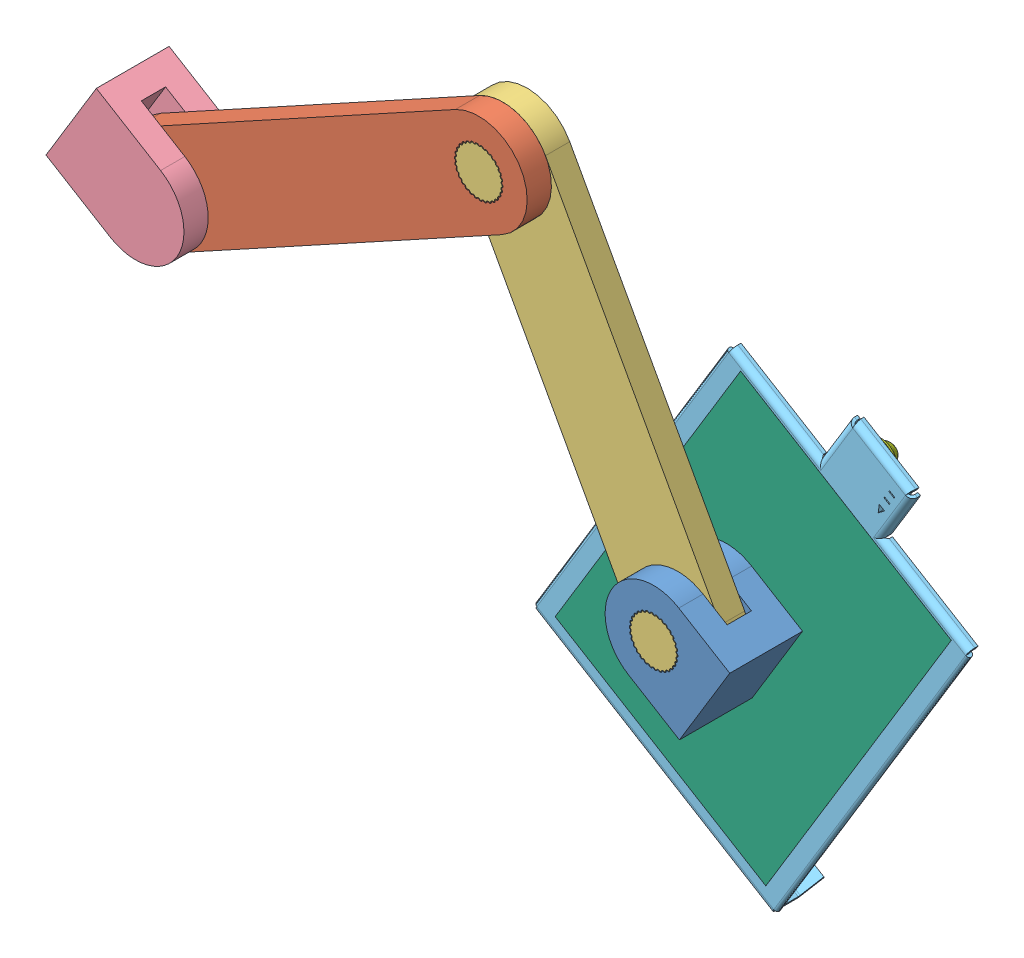
SolidWorks assembly movies, configuration Default. Lengths in mm.
Overall size (844.27 585.2 400.69).
9 component instances, 7 part files, 4 mates.
Components (placement in the parent):
- movie screen arm-1: movie screen arm [Default] at (19.653 64.9942 60.0694) size (271.91 188.53 40) (flexible)
  - Screen Arm Mount-1: Screen Arm Mount [Default] at (460.6698 -286.8749 -10.3389) x (-0.518973 -0.85479 0) z (0 0 1) size (40 44.59 30)
  - Arm 1-1: Arm 1 [Default] at (319.3618 -78.7079 -0.3389) x (0.480784 -0.876839 0) z (0.876839 0.480784 0) size (40 10 190)
  - Arm 2-1: Arm 2 [Default] at (269.2199 -30.9413 -20.3389) x (-0.876839 -0.480784 0) z (0 0 1) size (40 190 20)
  - mount thing do wak-1: mount thing do wak [Default] at (185.9995 -147.4762 -10.3389) x (-0.518973 -0.85479 0) z (0 0 1) size (40 50.99 30)
- sweet screen-1: sweet screen [Default] at (440.6658 467.0414 657.6815) x (0.167909 -0.686882 0.707107) z (0.167909 -0.686882 -0.707107) size (283.33 771.18 283.33)
  - Frame-1: Frame [Default] at (20.3068 185.0949 880.7989) size (283.33 771.18 283.33)
  - glass panel for god screen-1: glass panel for god screen [Default] at (-40.715 166.9153 847.3418) x (0.5 0.707107 0.5) z (-0.707107 0 0.707107) size (147.32 101.6 2.54)
  - Button Dial-1: Button Dial [Default] at (-81.6373 96.2697 838.5954) x (0.5 -0.707107 0.5) z (0.5 0.707107 0.5) size (15.23 13.25 15.23)
Mates (geometry in assembly coordinates):
- Coincident1: coincident anti-aligned: plane of movie screen arm-1/Screen Arm Mount-1 through (409.296 -141.8903 29.7305) normal (0 0 -1); plane of sweet screen-1/glass panel for god screen-1 through (413.9643 -126.6514 29.7305) normal (0 0 1)
- Width1: width aligned: plane of sweet screen-1/Frame-1 through (410.2251 -53.3098 28.4546) normal (0.518973 0.85479 0); plane of sweet screen-1/Frame-1 through (331.1336 -183.5799 28.4546) normal (-0.518973 -0.85479 0); plane of movie screen arm-1/Screen Arm Mount-1 through (419.6754 -124.7945 59.7305) normal (0.518973 0.85479 0); plane of movie screen arm-1/Screen Arm Mount-1 through (398.9165 -158.9862 59.7305) normal (-0.518973 -0.85479 0)
- Distance1: distance = 44.5348 mm aligned: plane of movie screen arm-1/Screen Arm Mount-1 through (440.6934 -137.5553 59.7305) normal (0.85479 -0.518973 0); plane of sweet screen-1/Frame-1 through (428.8361 -242.8985 27.2346) normal (0.85479 -0.518973 0)
- Parallel1: parallel aligned: plane of movie screen arm-1/mount thing do wak-1 through (168.7815 -83.4938 39.7305) normal (-0.85479 0.518973 0); plane of sweet screen-1/Frame-1 through (330.5376 -184.5615 19.0785) normal (-0.85479 0.518973 0)
